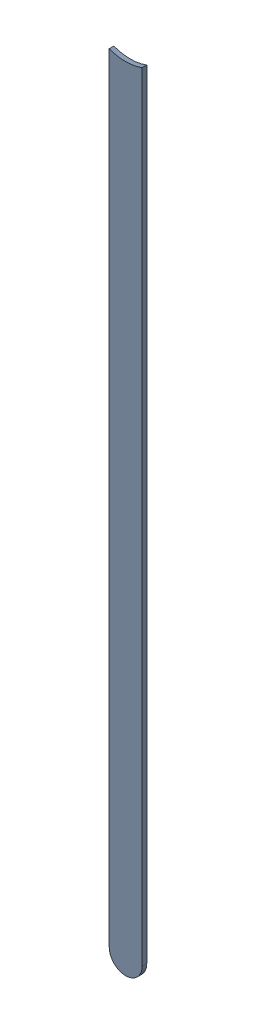
SolidWorks assembly Track (17.2mm,51.761mm)(17.2mm,58.1mm) on Bottom Layer, configuration Predeterminado. Lengths in mm.
Overall size (0.25 6.13 0.04).
2 component instances, 1 part files, 0 mates.
Components (placement in the parent):
- Track (17.2mm,51.761mm)(17.2mm,58.1mm) on Bottom Layer-1-1: Track (17.2mm,51.761mm)(17.2mm,58.1mm) on Bottom Layer-1 [Predeterminado] at (-68.317 -44.187 -0.4013) size (0.25 6.13 0.04)
  - Track (17.2mm,51.761mm)(17.2mm,58.1mm) on Bottom Layer-Part-1-1: Track (17.2mm,51.761mm)(17.2mm,58.1mm) on Bottom Layer-Part-1 [Predeterminado] at origin size (0.25 6.13 0.04)
